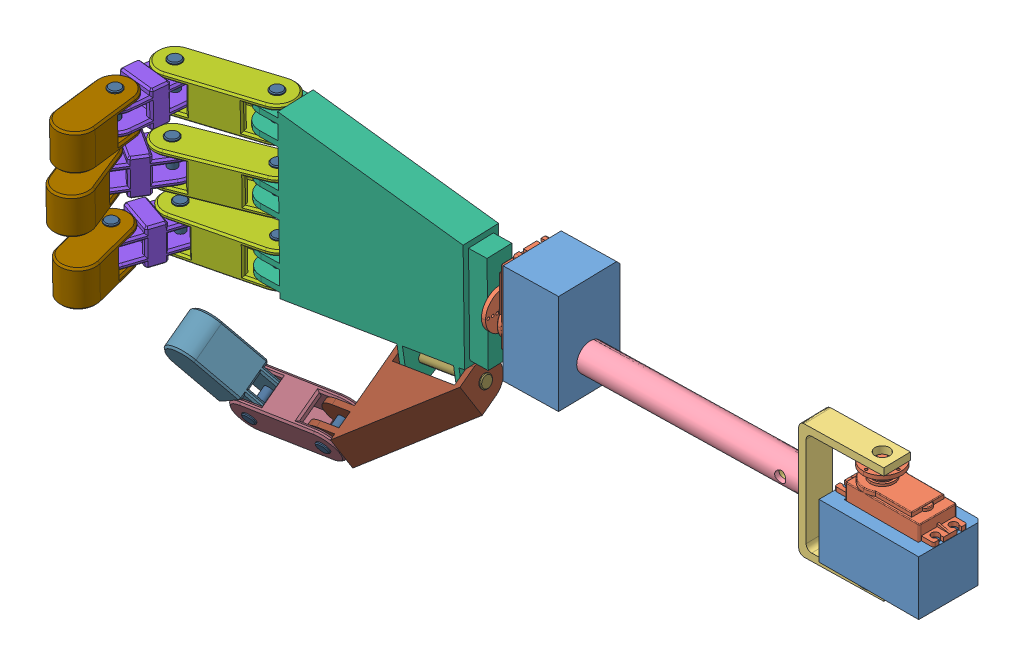
SolidWorks assembly arm1, configuration Default. Lengths in mm.
Overall size (447.59 140.28 107.88).
37 component instances, 14 part files, 19 mates.
Components (placement in the parent):
- servo holder-1: servo holder [Default] at (-12.9585 -17.2041 11.4568) size (55 42 34.74)
- Servo Motor MG996R.STEP-1: Servo Motor MG996R.STEP [Default] at (14.5415 -16.0741 -6.2334) size (55.8 47.4 21)
- arm bracket-1: arm bracket [Default] at (12.4483 31.3259 1.0958) x (-0.999776 0 0.021142) z (-0.021142 0 -0.999776) size (61 63.76 15)
- wrist-1: wrist [Default] at (-33.7 3.4442 -5.43) x (0 -1 0) z (-0.021142 0 -0.999776) size (15 120 15)
- instrument ball bearing_68_am-1: instrument ball bearing_68_am [AFBMA 12.1.4.1 - 0080-22 - 8,SI,NC,8_68] at (4.2915 -20.9374 -6.2334) x (0 1 0) z (-0.145367 0 0.989378) size (7 22 22)
- servo holder-2: servo holder [Default] at (-153.2992 -13.8058 14.7933) x (0 1 0) z (0.021142 0 0.999776) size (55 42 34.74)
- Servo Motor MG996R.STEP-2: Servo Motor MG996R.STEP [Default] at (-154.8729 13.6942 -2.8675) x (0 1 0) z (0.021142 0 0.999776) size (55.8 47.4 21)
- Robot_Hand_Left-1: Robot_Hand_Left [Default] at (-312.2378 3.4442 0.4602) x (-0.000279 -0.999913 -0.01319) z (0.999776 0 -0.021142) size (139 98.15 202.96)
  - hand_palm_left-1: hand_palm_left [Default] at origin size (100.27 20 130)
  - Robot_Finger-1: Robot_Finger [Default] at (35 0 -10) x (0 0.213225 0.977003) z (-1 0 0) size (75.56 77.26 22) (flexible)
    - finger_inner-1: finger_inner [Default] at (-22.5 0 0) x (-1 0 0) z (0 0 -1) size (65 20 20)
    - finger_middle-1: finger_middle [Default] at (-53.0486 -12.6578 0) x (-0.536574 -0.843853 0) z (0 0 -1) size (50 20 20)
    - finger_top-1: finger_top [Default] at (-61.0395 -37.8155 0) x (0.004615 -0.999989 0) z (0 0 -1) size (45 20 20)
    - finger_connector-1: finger_connector [Default] x (1 0 0) z (0 0 -1) size (7 7 22)
    - finger_connector-2: finger_connector [Default] at (-45 0 0) x (0.843853 -0.536574 0) z (0 0 -1) size (7 7 22)
    - finger_connector-3: finger_connector [Default] at (-61.0972 -25.3156 0) x (0.004615 -0.999989 0) z (0 0 -1) size (7 7 22)
  - Robot_Finger-2: Robot_Finger [Default] at (0 0 -10) x (0 0.343168 0.939274) z (-1 0 0) size (75.56 77.26 22) (flexible)
    - finger_inner-1: finger_inner [Default] at (-22.5 0 0) x (-1 0 0) z (0 0 -1) size (65 20 20)
    - finger_middle-1: finger_middle [Default] at (-57.1246 -8.8315 0) x (-0.808304 -0.588765 0) z (0 0 -1) size (50 20 20)
    - finger_top-1: finger_top [Default] at (-69.1984 -30.1629 0) x (0.004054 -0.999992 0) z (0 0 -1) size (45 20 20)
    - finger_connector-1: finger_connector [Default] x (1 0 0) z (0 0 -1) size (7 7 22)
    - finger_connector-2: finger_connector [Default] at (-45 0 0) x (0.588765 -0.808304 0) z (0 0 -1) size (7 7 22)
    - finger_connector-3: finger_connector [Default] at (-69.2491 -17.663 0) x (0.004054 -0.999992 0) z (0 0 -1) size (7 7 22)
  - Robot_Finger-3: Robot_Finger [Default] at (-35 0 -10) x (0 0.276691 0.960959) z (-1 0 0) size (75.56 77.26 22) (flexible)
    - finger_inner-1: finger_inner [Default] at (-22.5 0 0) x (-1 0 0) z (0 0 -1) size (65 20 20)
    - finger_middle-1: finger_middle [Default] at (-50.9409 -13.7734 0) x (-0.396057 -0.918226 0) z (0 0 -1) size (50 20 20)
    - finger_top-1: finger_top [Default] at (-59.2354 -39.8232 0) x (-0.188295 -0.982113 0) z (0 0 -1) size (45 20 20)
    - finger_connector-1: finger_connector [Default] x (1 0 0) z (0 0 -1) size (7 7 22)
    - finger_connector-2: finger_connector [Default] at (-45 0 0) x (0.918226 -0.396057 0) z (0 0 -1) size (7 7 22)
    - finger_connector-3: finger_connector [Default] at (-56.8817 -27.5468 0) x (-0.188295 -0.982113 0) z (0 0 -1) size (7 7 22)
  - thumb_plate-1: thumb_plate [Default] at (44.6516 -8.7642 102.1977) x (0.476226 -0.876417 0.071434) z (-0.14834 0 0.988936) size (60 20 60)
  - thumb_plate_connector-1: thumb_plate_connector [Default] at (42.8562 0 81.7047) x (0.476226 -0.876417 0.071434) z (-0.14834 0 0.988936) size (7 7 42)
  - Robot_Thumb-1: Robot_Thumb [Default] at (66.3554 -35.0567 54.8939) x (0.133192 -0.008404 -0.991055) z (0.476226 -0.876417 0.071434) size (71.84 58.36 22) (flexible)
    - thumb_inner-1: thumb_inner [Default] at (20 0 0) size (60 20 20)
    - thumb_top-1: thumb_top [Default] at (48.8569 -15.0932 0) x (0.506106 -0.862471 0) z (0 0 1) size (55 20 20)
    - finger_connector-1: finger_connector [Default] at origin size (7 7 22)
    - finger_connector-2: finger_connector [Default] at (40 0 0) x (0.506106 -0.862471 0) z (0 0 1) size (7 7 22)
Mates (geometry in assembly coordinates):
- Coincident1: coincident anti-aligned: plane of servo holder-1 through (-5.9585 -16.0741 -16.4834) normal (0 0 1); plane of Servo Motor MG996R.STEP-1 through (-5.9585 20.9259 -16.4834) normal (0 0 -1)
- Coincident2: coincident anti-aligned: plane of servo holder-1 through (35.0415 -16.0741 -16.4834) normal (-1 0 0); plane of Servo Motor MG996R.STEP-1 through (35.0415 20.9259 4.0166) normal (1 0 0)
- Coincident3: coincident anti-aligned: plane of servo holder-1 through (-12.9585 -16.0741 11.4568) normal (0 1 0); plane of Servo Motor MG996R.STEP-1 through (14.5415 -16.0741 -6.2334) normal (0 -1 0)
- Coincident4: coincident anti-aligned: plane of Servo Motor MG996R.STEP-1 through (4.2915 31.3259 -6.2334) normal (0 1 0); plane of arm bracket-1 through (12.1311 31.3259 -13.9008) normal (0 -1 0)
- Concentric2: concentric aligned: cylinder of arm bracket-1 through (-48.6967 3.4442 -5.1128) axis (0.999776 0 -0.021142) radius 5; cylinder of wrist-1 through (-48.6967 3.4442 -5.1128) axis (0.999776 0 -0.021142) radius 5
- Coincident6: coincident anti-aligned: plane of arm bracket-1 through (-33.8586 35.3259 -12.9283) normal (-0.999776 0 0.021142); plane of wrist-1 through (-33.7 3.4442 -5.43) normal (0.999776 0 -0.021142)
- Concentric3: concentric anti-aligned: cylinder of arm bracket-1 through (-43.6872 3.4442 -4.7187) axis (0.021142 0 0.999776) radius 3; cylinder of wrist-1 through (-43.4864 3.4442 4.7792) axis (-0.021142 0 -0.999776) radius 3
- Concentric4: concentric aligned: circle of arm bracket-1; cylinder of instrument ball bearing_68_am-1 through (4.2915 -41.5749 -6.2334) axis (0 1 0) radius 4
- Coincident8: coincident anti-aligned: plane of arm bracket-1 through (-29.8595 -24.4374 -13.0129) normal (0 1 0); plane of instrument ball bearing_68_am-1 through (-4.514 -24.4374 -7.5271) normal (0 -1 0)
- Concentric5: concentric aligned: circle of Servo Motor MG996R.STEP-1; cylinder of arm bracket-1 through (4.2915 -28.4374 -6.2334) axis (0 1 0) radius 4
- Concentric6: concentric aligned: cylinder of wrist-1 through (-141.6759 3.4442 -3.1466) axis (-0.999776 0 0.021142) radius 4; cylinder of servo holder-2 through (-141.6759 3.4442 -3.1466) axis (-0.999776 0 0.021142) radius 4
- Coincident9: coincident anti-aligned: plane of wrist-1 through (-153.6732 3.4442 -2.8929) normal (-0.999776 0 0.021142); plane of servo holder-2 through (-153.2992 -13.8058 14.7933) normal (0.999776 0 -0.021142)
- Parallel2: parallel aligned: plane of arm bracket-1 through (12.4483 31.3259 1.0958) normal (0.021142 0 0.999776); plane of servo holder-2 through (-183.2925 -13.8058 15.4275) normal (0.021142 0 0.999776)
- Coincident13: coincident anti-aligned: plane of servo holder-2 through (-155.0197 -6.8058 -13.1167) normal (0.021142 0 0.999776); plane of Servo Motor MG996R.STEP-2 through (-192.0814 -6.8058 -12.333) normal (-0.021142 0 -0.999776)
- Coincident15: coincident anti-aligned: plane of servo holder-2 through (-162.3453 -3.8058 -6.2103) normal (0.999776 0 -0.021142); plane of Servo Motor MG996R.STEP-2 through (-162.3453 -7.8058 -6.2103) normal (-0.999776 0 0.021142)
- Coincident16: coincident anti-aligned: plane of servo holder-2 through (-155.0197 -6.8058 -13.1167) normal (0 1 0); plane of Servo Motor MG996R.STEP-2 through (-191.648 -6.8058 8.1624) normal (0 -1 0)
- Width2: width: plane of Robot_Hand_Left-1/hand_palm_left-1 through (-312.0138 48.3084 11.0506) normal (0.02114 -0.013193 0.999689); plane of Servo Motor MG996R.STEP-2 through (-312.4366 48.5722 -8.9431) normal (-0.02114 0.013193 -0.999689); cylinder of Robot_Hand_Left-1/hand_palm_left-1 through (-202.2623 3.4442 -1.8654) axis (0.999776 0 -0.021142) radius 10.5
- Coincident20: coincident anti-aligned: plane of Servo Motor MG996R.STEP-2 through (-202.2623 3.4442 -1.8654) normal (-0.999776 0 0.021142); plane of Robot_Hand_Left-1/hand_palm_left-1 through (-202.2623 3.4442 -1.8654) normal (0.999776 0 -0.021142)
- Width3: width: plane of Robot_Hand_Left-1/hand_palm_left-1 through (-202.4028 30.5007 -8.5076) normal (0.000279 0.999913 0.01319); plane of Servo Motor MG996R.STEP-2 through (-202.4178 -23.4275 -9.2189) normal (-0.000279 -0.999913 -0.01319); cylinder of Robot_Hand_Left-1/hand_palm_left-1 through (-202.2623 3.4442 -1.8654) axis (0.999776 0 -0.021142) radius 10.5
